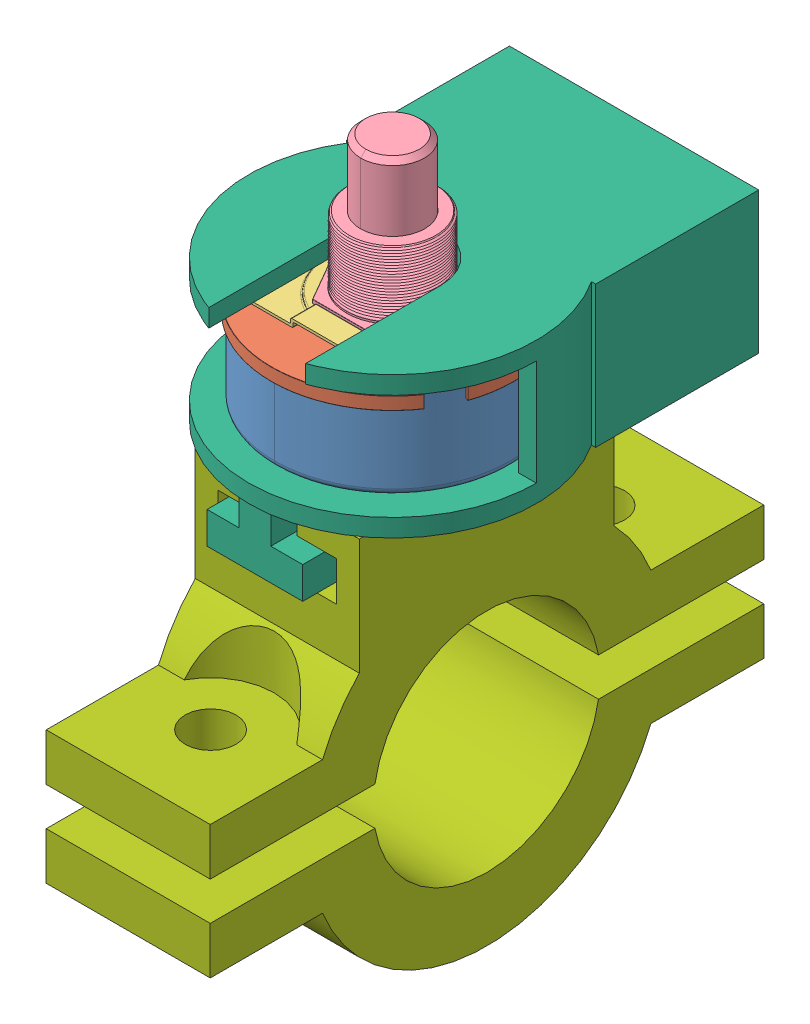
SolidWorks assembly pot, configuration Default. Lengths in mm.
Overall size (28.65 66.25 55.16).
10 component instances, 7 part files, 7 mates.
Components (placement in the parent):
- Fender_Pot.STEP-1: Fender_Pot.STEP [Default] at origin size (24.13 23 33.88)
  - Fender_Pot_Body.STEP-1: Fender_Pot_Body.STEP [Default] at (6.4584 10.2926 19.7539) size (23.5 9.41 23.5)
  - Fender_Pot_SiPlate.STEP-1: Fender_Pot_SiPlate.STEP [Default] at (6.4519 17.9126 19.7812) size (24.13 1.27 28.55)
  - Fender_Pot_TopPlate.STEP-1: Fender_Pot_TopPlate.STEP [Default] at (6.4584 19.1826 19.7539) size (22.13 0.76 15.24)
  - FenderPot_Shaft.STEP-1: FenderPot_Shaft.STEP [Default] at (6.4584 19.6906 19.7539) size (11.68 13.59 10.48)
  - FenderPot_Lead.STEP-1: FenderPot_Lead.STEP [Default] at (11.4114 10.2926 8.0972) x (0 0 -1) z (0 -1 0) size (10.16 3.81 9.14)
  - FenderPot_Lead.STEP-2: FenderPot_Lead.STEP [Default] at (4.5534 10.2926 8.0972) x (0 0 -1) z (0 -1 0) size (10.16 3.81 9.14)
  - FenderPot_Lead.STEP-3: FenderPot_Lead.STEP [Default] at (-2.3046 10.2926 8.0972) x (0 0 -1) z (0 -1 0) size (10.16 3.81 9.14)
- Part6^pot-1: Part6^pot [Default] at (6.4584 10.2926 19.7539) x (-1 0 0) z (0 -1 0) size (28.65 38.39 20.45) (virtual)
- potclamp-1: potclamp [Default] at (-1.3325 -15.3165 18.9263) x (0 -1 0) z (0 0 1) size (41.48 16.34 55.16)
Mates (geometry in assembly coordinates):
- InPlace1: in place: plane of Fender_Pot.STEP-1/Fender_Pot_Body.STEP-1 through (6.4584 10.2926 19.7539) normal (0 -1 0); plane of ? through (0 10.2926 0) normal (0 -1 0); moOrthogonalPlaneRef_w of Fender_Pot.STEP-1/Fender_Pot_Body.STEP-1 through (6.4584 10.2926 19.7539) normal (0 -1 0); plane of ? through (0 10.2926 0) normal (0 0 -1); plane of Fender_Pot.STEP-1/Fender_Pot_Body.STEP-1 through (6.4584 10.2926 19.7539) normal (0 -1 0); plane of ? through (0 10.2926 0) normal (-1 0 0); plane of Fender_Pot.STEP-1/Fender_Pot_Body.STEP-1 through (6.4584 10.2926 19.7539) normal (0 -1 0); unknown of Part6^pot-1
- Coincident1: coincident aligned: plane of Fender_Pot.STEP-1/Fender_Pot_Body.STEP-1; plane of Part6^pot-1
- Coincident2: coincident aligned: moOrthogonalPlaneRef_w of Fender_Pot.STEP-1/Fender_Pot_Body.STEP-1 through (6.4584 10.2926 19.7539) normal (0 0 -1); plane of Part6^pot-1 through (6.4584 10.2926 19.7539) normal (0 0 -1)
- Coincident3: coincident anti-aligned: moOrthogonalPlaneRef_w of Fender_Pot.STEP-1/Fender_Pot_Body.STEP-1 through (6.4584 10.2926 19.7539) normal (1 0 0); plane of Part6^pot-1 through (6.4584 10.2926 19.7539) normal (-1 0 0)
- Parallel1: parallel anti-aligned: plane of Part6^pot-1 through (6.4584 2.1646 33.4699) normal (0 -1 0); plane of potclamp-1 through (-1.3325 1.7582 6.2263) normal (0 1 0)
- Coincident1: coincident anti-aligned: plane of Part6^pot-1 through (4.8709 10.2926 33.4699) normal (-1 0 0); plane of potclamp-1 through (4.8709 -15.3165 6.2263) normal (1 0 0)
- Coincident2: coincident anti-aligned: plane of Part6^pot-1 through (6.4584 8.5146 19.7539) normal (0 -1 0); plane of potclamp-1 through (-1.3325 8.5146 6.2263) normal (0 1 0)
